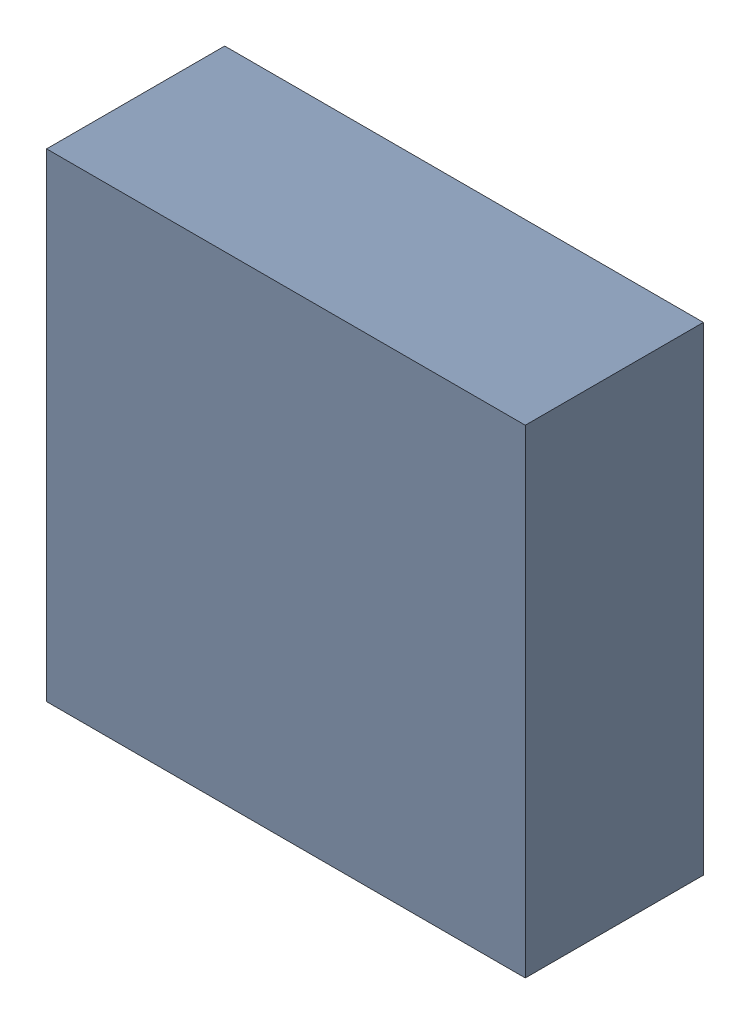
SolidWorks assembly Q2, configuration ﾃﾞﾌｫﾙﾄ. Lengths in mm.
Overall size (2.15 2.15 0.8).
2 component instances, 1 part files, 0 mates.
Components (placement in the parent):
- 689261240-1: 689261240 [ﾃﾞﾌｫﾙﾄ] at (10.4775 20.0025 0) size (2.15 2.15 0.8)
  - Extruded_30-1: Extruded_30 [ﾃﾞﾌｫﾙﾄ] at origin size (2.15 2.15 0.8)
